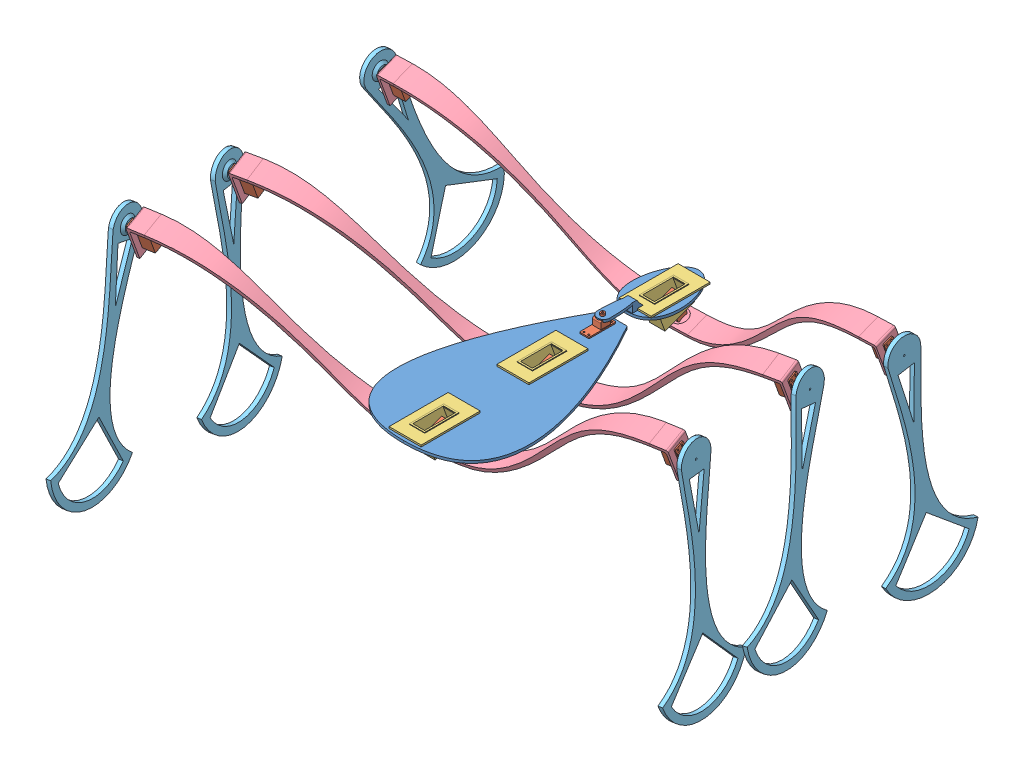
SolidWorks assembly robot2_assemblage2, configuration Défaut. Lengths in mm.
Overall size (643.31 325.54 587.43).
23 component instances, 5 part files, 54 mates.
Components (placement in the parent):
- robot2_corps-1: robot2_corps [Défaut] at (-13.7924 -2.8814 70) size (175.25 14 350)
- servo2-1: servo2 [Défaut] at (-19.7224 0.1186 -43.632) x (1 0 0) z (0 1 0) size (11.43 32.26 30.46)
- robot2_porteservo-1: robot2_porteservo [Défaut] at (-20.7924 2.1186 -152.2504) size (38 34.59 70)
- robot2_porteservo-2: robot2_porteservo [Défaut] at (-24.7924 2.1186 -11.4779) size (38 34.59 70)
- robot2_porteservo-3: robot2_porteservo [Défaut] at (-24.7924 2.1186 116.2324) size (38 34.59 70)
- servo2-2: servo2 [Défaut] at (-10.2924 -29.1623 10.4944) x (-1 0 0) z (0 -0.939693 -0.34202) size (11.43 32.26 30.46)
- servo2-3: servo2 [Défaut] at (-5.8624 -29.1623 -130.2781) x (-1 0 0) z (0 -0.939693 -0.34202) size (11.43 32.26 30.46)
- servo2-4: servo2 [Défaut] at (-10.2924 -29.1623 138.2047) x (-1 0 0) z (0 -0.939693 -0.34202) size (11.43 32.26 30.46)
- robot2_bras-1: robot2_bras [Défaut] at (-11.8681 -28.7459 -161.9408) x (0.99973 0.007954 -0.021852) z (0.023255 -0.341928 0.939439) size (580 158 25)
- robot2_bras-2: robot2_bras [Défaut] at (-17.9186 -28.795 -21.0333) x (0.988242 0.052294 -0.143675) z (0.152896 -0.337999 0.928644) size (580 158 25)
- robot2_bras-3: robot2_bras [Défaut] at (-17.5496 -28.7774 106.6286) x (0.99236 0.042198 -0.115938) z (0.123378 -0.339407 0.932513) size (580 158 25)
- servo2-5: servo2 [Défaut] at (-301.6369 80.0581 -108.1729) x (0.023255 -0.341928 0.939439) z (-0.99973 -0.007954 0.021852) size (11.43 32.26 30.46)
- servo2-6: servo2 [Défaut] at (-303.4386 67.0309 68.3916) x (0.152896 -0.337999 0.928644) z (-0.988242 -0.052294 0.143675) size (11.43 32.26 30.46)
- servo2-7: servo2 [Défaut] at (271.4895 93.4978 -4.3257) x (-0.152896 0.337999 -0.928644) z (0.988242 0.052294 -0.143675) size (11.43 32.26 30.46)
- servo2-8: servo2 [Défaut] at (278.4721 80.763 -110.1095) x (-0.023255 0.341928 -0.939439) z (0.99973 0.007954 -0.021852) size (11.43 32.26 30.46)
- robot2_pied-1: robot2_pied [Défaut] at (289.7741 99.1578 -109.7776) x (0.99973 0.007954 -0.021852) z (0.022767 -0.143248 0.989425) size (8 280 113.14)
- robot2_pied-2: robot2_pied [Défaut] at (281.9193 112.3773 -5.3255) x (0.988242 0.052294 -0.143675) z (0.129471 0.213637 0.968296) size (8 280 113.14)
- robot2_pied-3: robot2_pied [Défaut] at (-312.9389 94.3627 -96.6033) x (-0.99973 -0.007954 0.021852) z (-0.023113 0.443546 -0.895953) size (8 280 113.14)
- robot2_pied-4: robot2_pied [Défaut] at (-313.8683 80.8508 81.293) x (-0.988242 -0.052294 0.143675) z (-0.144333 0.009011 -0.989488) size (8 280 113.14)
- servo2-9: servo2 [Défaut] at (272.5086 90.5617 131.4515) x (-0.123378 0.339407 -0.932513) z (0.99236 0.042198 -0.115938) size (11.43 32.26 30.46)
- servo2-10: servo2 [Défaut] at (-304.4703 70.3122 188.1625) x (0.123378 -0.339407 0.932513) z (-0.99236 -0.042198 0.115938) size (11.43 32.26 30.46)
- robot2_pied-5: robot2_pied [Défaut] at (283.1541 109.3338 130.7469) x (0.99236 0.042198 -0.115938) z (0.115938 0.002456 0.993253) size (8 280 113.14)
- robot2_pied-6: robot2_pied [Défaut] at (-315.1158 84.2396 200.7688) x (-0.99236 -0.042198 0.115938) z (-0.100195 -0.272698 -0.956868) size (8 280 113.14)
Mates (geometry in assembly coordinates):
- Coïncidente1: coincident anti-aligned: plane of robot2_corps-1 through (-19.2924 0.1186 -67) normal (0 0 1); plane of servo2-1 through (-8.2924 -16.8994 -67) normal (0 0 -1)
- Coïncidente2: coincident anti-aligned: plane of robot2_corps-1 through (-8.2924 0.1186 -67) normal (-1 0 0); plane of servo2-1 through (-8.2924 0.1186 -43.632) normal (1 0 0)
- Coïncidente3: coincident anti-aligned: plane of robot2_corps-1 through (56.9131 0.1186 51.982) normal (0 1 0); plane of servo2-1 through (-8.2924 0.1186 -67) normal (0 -1 0)
- Coïncidente9: coincident anti-aligned: plane of robot2_corps-1 through (14.2791 0.1186 -132.5) normal (0 1 0); plane of robot2_porteservo-1 through (-2.7924 0.1186 -152.2504) normal (0 -1 0)
- Coïncidente10: coincident anti-aligned: plane of robot2_corps-1 through (-2.7924 0.1186 -160) normal (-1 0 0); plane of robot2_porteservo-1 through (-2.7924 2.1186 -152.2504) normal (1 0 0)
- Coïncidente12: coincident anti-aligned: plane of robot2_corps-1 through (-24.7924 0.1186 -20) normal (1 0 0); plane of robot2_porteservo-2 through (-24.7924 2.1186 -11.4779) normal (-1 0 0)
- Coïncidente13: coincident anti-aligned: plane of robot2_corps-1 through (56.9131 0.1186 51.982) normal (0 1 0); plane of robot2_porteservo-2 through (-6.7924 0.1186 -11.4779) normal (0 -1 0)
- Coïncidente14: coincident anti-aligned: plane of robot2_corps-1 through (-24.7924 0.1186 110) normal (1 0 0); plane of robot2_porteservo-3 through (-24.7924 2.1186 116.2324) normal (-1 0 0)
- Coïncidente15: coincident anti-aligned: plane of robot2_corps-1 through (56.9131 0.1186 51.982) normal (0 1 0); plane of robot2_porteservo-3 through (-6.7924 0.1186 116.2324) normal (0 -1 0)
- Coïncidente16: coincident anti-aligned: plane of robot2_porteservo-2 through (-6.7924 -31.531 17.0026) normal (0 -0.939693 -0.34202); plane of servo2-2 through (-21.7224 -21.1699 -11.4643) normal (0 0.939693 0.34202)
- Coïncidente17: coincident anti-aligned: plane of robot2_porteservo-2 through (-10.2924 10.03 24.3676) normal (-1 0 0); plane of servo2-2 through (-10.2924 -29.1623 10.4944) normal (1 0 0)
- Coïncidente18: coincident anti-aligned: plane of robot2_porteservo-2 through (-21.2924 17.8965 2.7547) normal (0 -0.34202 0.939693); plane of servo2-2 through (-21.7224 -5.1782 -5.6438) normal (0 0.34202 -0.939693)
- Coïncidente19: coincident anti-aligned: plane of robot2_porteservo-1 through (-17.2924 10.03 -116.4049) normal (1 0 0); plane of servo2-3 through (-17.2924 -29.1623 -130.2781) normal (-1 0 0)
- Coïncidente20: coincident anti-aligned: plane of robot2_porteservo-1 through (-17.2924 17.8965 -138.0178) normal (0 -0.34202 0.939693); plane of servo2-3 through (-17.2924 -5.1782 -146.4164) normal (0 0.34202 -0.939693)
- Coïncidente21: coincident anti-aligned: plane of robot2_porteservo-1 through (-2.7924 -31.531 -123.7699) normal (0 -0.939693 -0.34202); plane of servo2-3 through (-17.2924 -30.6825 -126.1012) normal (0 0.939693 0.34202)
- Coïncidente22: coincident anti-aligned: plane of robot2_porteservo-3 through (-10.2924 10.03 152.078) normal (-1 0 0); plane of servo2-4 through (-10.2924 -29.1623 138.2047) normal (1 0 0)
- Coïncidente23: coincident anti-aligned: plane of robot2_porteservo-3 through (-21.2924 17.8965 130.465) normal (0 -0.34202 0.939693); plane of servo2-4 through (-21.7224 -5.1782 122.0665) normal (0 0.34202 -0.939693)
- Coïncidente24: coincident anti-aligned: plane of robot2_porteservo-3 through (-6.7924 -31.531 144.7129) normal (0 -0.939693 -0.34202); plane of servo2-4 through (-21.7224 -21.1699 116.246) normal (0 0.939693 0.34202)
- Coaxiale1: concentric aligned: circle of servo2-3; circle of robot2_bras-1
- Coïncidente26: coincident anti-aligned: plane of servo2-3 through (-14.0774 -35.839 -151.2239) normal (0 -0.939693 -0.34202); plane of robot2_bras-1 through (-11.5774 -35.839 -151.2239) normal (0 0.939693 0.34202)
- Coaxiale2: concentric aligned: circle of servo2-2; circle of robot2_bras-2
- Coïncidente28: coincident anti-aligned: plane of servo2-2 through (-18.5074 -35.839 -10.4514) normal (0 -0.939693 -0.34202); plane of robot2_bras-2 through (-16.0074 -35.839 -10.4514) normal (0 0.939693 0.34202)
- Coaxiale3: concentric aligned: circle of servo2-4; circle of robot2_bras-3
- Coïncidente30: coincident anti-aligned: plane of servo2-4 through (-18.5074 -35.839 117.259) normal (0 -0.939693 -0.34202); plane of robot2_bras-3 through (-16.0074 -35.839 117.259) normal (0 0.939693 0.34202)
- Coïncidente31: coincident anti-aligned: plane of robot2_bras-1 through (-289.3743 98.2041 -89.7051) normal (-0.023255 0.341928 -0.939439); plane of servo2-5 through (-301.3711 76.1499 -97.4352) normal (0.023255 -0.341928 0.939439)
- Coïncidente32: coincident anti-aligned: plane of robot2_bras-1 through (-289.3743 98.2041 -89.7051) normal (0 -0.939693 -0.34202); plane of servo2-5 through (-284.3577 98.244 -89.8147) normal (0 0.939693 0.34202)
- Coïncidente33: coincident anti-aligned: plane of robot2_bras-1 through (-301.2083 105.1121 -79.4466) normal (-0.99973 -0.007954 0.021852); plane of servo2-5 through (-301.3711 71.973 -98.9554) normal (0.99973 0.007954 -0.021852)
- Coïncidente34: coincident anti-aligned: plane of robot2_bras-2 through (-289.8978 85.8992 84.8749) normal (0 -0.939693 -0.34202); plane of servo2-6 through (-284.8731 86.0162 84.5533) normal (0 0.939693 0.34202)
- Coïncidente35: coincident anti-aligned: plane of robot2_bras-2 through (-291.5797 89.6172 74.6598) normal (0.152896 -0.337999 0.928644); plane of servo2-6 through (-303.4386 67.0309 68.3916) normal (-0.152896 0.337999 -0.928644)
- Coïncidente36: coincident anti-aligned: plane of robot2_bras-2 through (-300.6864 92.3026 96.5197) normal (-0.988242 -0.052294 0.143675); plane of servo2-6 through (-301.691 85.1263 86.9983) normal (0.988242 0.052294 -0.143675)
- Coïncidente37: coincident anti-aligned: plane of robot2_bras-2 through (257.883 118.6924 -5.2237) normal (0.152896 -0.337999 0.928644); plane of servo2-7 through (269.7419 97.3612 -14.9401) normal (-0.152896 0.337999 -0.928644)
- Coïncidente38: coincident anti-aligned: plane of robot2_bras-2 through (259.5649 114.9744 4.9914) normal (0 -0.939693 -0.34202); plane of servo2-7 through (252.924 118.43 -4.5027) normal (0 0.939693 0.34202)
- Coïncidente39: coincident anti-aligned: plane of robot2_bras-2 through (272.4941 122.6329 13.188) normal (0.988242 0.052294 -0.143675); plane of servo2-7 through (269.7419 119.3199 -6.9478) normal (-0.988242 -0.052294 0.143675)
- Coïncidente40: coincident anti-aligned: plane of robot2_bras-1 through (266.4753 102.6263 -101.855) normal (-0.023255 0.341928 -0.939439); plane of servo2-8 through (278.4721 80.763 -110.1095) normal (0.023255 -0.341928 0.939439)
- Coïncidente41: coincident anti-aligned: plane of robot2_bras-1 through (266.4753 102.6263 -101.855) normal (0 -0.939693 -0.34202); plane of servo2-8 through (261.1929 106.4946 -112.4831) normal (0 0.939693 0.34202)
- Coïncidente42: coincident anti-aligned: plane of robot2_bras-1 through (278.6349 109.7251 -92.1209) normal (0.99973 0.007954 -0.021852); plane of servo2-8 through (278.2063 106.6299 -112.855) normal (-0.99973 -0.007954 0.021852)
- Coaxiale4: concentric aligned: circle of servo2-8; circle of robot2_pied-1
- Coïncidente43: coincident anti-aligned: plane of servo2-8 through (291.7154 100.0285 -112.1699) normal (0.99973 0.007954 -0.021852); plane of robot2_pied-1 through (291.7736 99.1737 -109.8213) normal (-0.99973 -0.007954 0.021852)
- Coaxiale5: concentric aligned: circle of servo2-7; circle of robot2_pied-2
- Coïncidente44: coincident anti-aligned: plane of servo2-7 through (283.5135 113.3269 -7.9344) normal (0.988242 0.052294 -0.143675); plane of robot2_pied-2 through (283.8957 112.4819 -5.6128) normal (-0.988242 -0.052294 0.143675)
- Coaxiale6: concentric aligned: circle of servo2-5; circle of robot2_pied-3
- Coïncidente45: coincident anti-aligned: plane of servo2-5 through (-314.8802 93.492 -94.211) normal (-0.99973 -0.007954 0.021852); plane of robot2_pied-3 through (-314.9383 94.3468 -96.5596) normal (0.99973 0.007954 -0.021852)
- Coaxiale7: concentric aligned: circle of servo2-6; circle of robot2_pied-4
- Coïncidente46: coincident anti-aligned: plane of servo2-6 through (-315.4625 79.9012 83.9019) normal (-0.988242 -0.052294 0.143675); plane of robot2_pied-4 through (-315.8448 80.7462 81.5803) normal (0.988242 0.052294 -0.143675)
- Coïncidente47: coincident anti-aligned: plane of robot2_bras-3 through (259.19 115.8935 130.1765) normal (0.123378 -0.339407 0.932513); plane of servo2-9 through (271.0983 94.4411 120.7929) normal (-0.123378 0.339407 -0.932513)
- Coïncidente48: coincident anti-aligned: plane of robot2_bras-3 through (260.5472 112.16 140.4341) normal (0 -0.939693 -0.34202); plane of servo2-9 through (254.2104 115.6818 130.7582) normal (0 0.939693 0.34202)
- Coïncidente49: coincident anti-aligned: plane of robot2_bras-3 through (273.3192 119.6875 148.9906) normal (0.99236 0.042198 -0.115938); plane of servo2-9 through (271.0983 116.3999 128.7852) normal (-0.99236 -0.042198 0.115938)
- Coïncidente50: coincident anti-aligned: plane of robot2_bras-3 through (-292.562 92.4315 194.6378) normal (0.123378 -0.339407 0.932513); plane of servo2-10 through (-304.4703 70.3122 188.1625) normal (-0.123378 0.339407 -0.932513)
- Coïncidente51: coincident anti-aligned: plane of robot2_bras-3 through (-291.2048 67.0851 197.0289) normal (0 0.939693 0.34202); plane of servo2-10 through (-303.0601 66.4328 198.8212) normal (0 -0.939693 -0.34202)
- Coïncidente52: coincident anti-aligned: plane of robot2_bras-3 through (-302.2495 95.2127 216.2344) normal (-0.99236 -0.042198 0.115938); plane of servo2-10 through (-303.0601 88.3915 206.8135) normal (0.99236 0.042198 -0.115938)
- Coaxiale8: concentric aligned: circle of servo2-9; circle of robot2_pied-5
- Coïncidente53: coincident anti-aligned: plane of servo2-9 through (284.8303 110.2667 128.1838) normal (0.99236 0.042198 -0.115938); plane of robot2_pied-5 through (285.1388 109.4182 130.515) normal (-0.99236 -0.042198 0.115938)
- Coaxiale9: concentric aligned: circle of servo2-10; circle of robot2_pied-6
- Coïncidente54: coincident anti-aligned: plane of servo2-10 through (-316.7921 83.3066 203.3319) normal (-0.99236 -0.042198 0.115938); plane of robot2_pied-6 through (-317.1005 84.1552 201.0006) normal (0.99236 0.042198 -0.115938)
